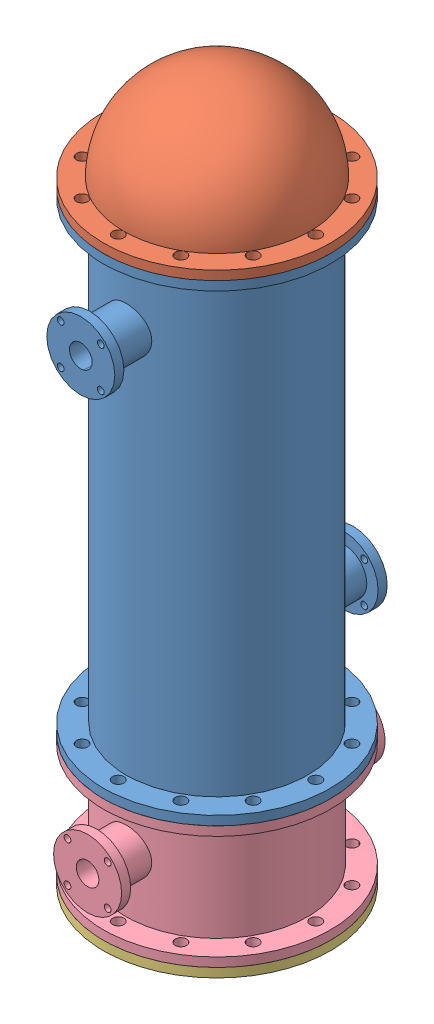
SolidWorks assembly Heat Exchangwr, configuration Default. Lengths in mm.
Overall size (500 1692.4 600).
12 component instances, 6 part files, 18 mates.
Components (placement in the parent):
- Tube Housing-1: Tube Housing [Default] at (499.3721 118.9236 1027.5542) size (500 1040 600)
- End Cap-1: End Cap [Default] at (499.3721 1158.9236 1027.5542) x (0 0 -1) z (1 0 0) size (500 225 500)
- Outside Flange-1: Outside Flange [Default] at (499.3721 -171.0764 1027.5542) size (500 20 500)
- Steam Channel-1: Steam Channel [Default] at (499.3721 -151.0764 1027.5542) size (500 540.34 580)
- Tubes and Holders-1: Tubes and Holders [Default] at (1394.8823 182.8892 1623.1997) x (0 1 0) z (-0.999974 0 -0.007153) size (1200 360 361.03)
  - Tubes-1: Tubes [Default] at (-63.9656 589.2251 899.7476) size (1200 360 360)
  - Semi flang-1: Semi flang [Default] at (96.0344 589.2251 910.6392) size (10 180 360)
  - Semi flang-2: Semi flang [Default] at (376.0344 589.2251 910.6392) size (10 180 360)
  - Semi flang-3: Semi flang [Default] at (806.0344 589.2251 910.6392) x (-1 0 0) z (0 0 1) size (10 180 360)
  - Semi flang-4: Semi flang [Default] at (656.0344 589.2251 910.6392) size (10 180 360)
  - Semi flang-5: Semi flang [Default] at (526.0344 589.2251 910.6392) x (-1 0 0) z (0 0 1) size (10 180 360)
  - Semi flang-6: Semi flang [Default] at (236.0344 589.2251 889.0756) x (1 0 0) z (0 0 -1) size (10 180 360)
Mates (geometry in assembly coordinates):
- Coincident1: coincident: plane of Tube Housing-1 through (499.3721 1158.9236 1027.5542) normal (0 1 0); plane of End Cap-1 through (499.3721 1158.9236 1027.5542) normal (0 -1 0)
- Distance1: distance = 0 mm: plane of End Cap-1 through (499.3721 1158.9236 1027.5542) normal (0 -1 0); plane of Tube Housing-1 through (499.3721 1158.9236 1027.5542) normal (0 1 0)
- Coincident3: coincident: circle of Tube Housing-1; cylinder of Tubes and Holders-1/Tubes-1 through (499.3721 138.9236 1027.5542) axis (0 -1 0) radius 180
- Coincident4: coincident: plane of Tube Housing-1 through (499.3721 118.9236 1027.5542) normal (0 -1 0); plane of Tubes and Holders-1/Tubes-1 through (499.3721 118.9236 1027.5542) normal (0 -1 0)
- Angle1: planar angle = 0 rad: cylinder of Tubes and Holders-1/Tubes-1 through (500.3352 118.9236 877.5573) axis (0 1 0) radius 7; cylinder of Tube Housing-1 through (499.3721 138.9236 1245.0542) axis (0 -1 0) radius 12.5
- Parallel5: parallel anti-aligned: plane of Tube Housing-1 through (499.3721 1158.9236 1027.5542) normal (0 1 0); plane of End Cap-1 through (499.3721 1158.9236 1027.5542) normal (0 -1 0)
- Distance3: distance = 20 mm: plane of Tube Housing-1 through (499.3721 1138.9236 1027.5542) normal (0 -1 0); plane of End Cap-1 through (499.3721 1158.9236 1027.5542) normal (0 -1 0)
- Coincident7: coincident anti-aligned: plane of Tube Housing-1 through (499.3721 118.9236 1027.5542) normal (0 -1 0); plane of Steam Channel-1 through (499.3721 118.9236 1027.5542) normal (0 1 0)
- Concentric3: concentric aligned: cylinder of Tube Housing-1 through (499.3721 1138.9236 1027.5542) axis (0 -1 0) radius 200; cylinder of Steam Channel-1 through (499.3721 98.9236 1027.5542) axis (0 -1 0) radius 200
- Concentric4: concentric: cylinder of Tube Housing-1 through (499.3721 1138.9236 1027.5542) axis (0 -1 0) radius 200; sphere of End Cap-1
- Parallel6: parallel aligned: plane of Tube Housing-1 through (499.3721 288.9236 727.5542) normal (0 0 -1); plane of Steam Channel-1 through (499.3721 -151.0764 732.5542) normal (0 0 -1)
- Parallel7: parallel: plane of Steam Channel-1 through (499.3721 -151.0764 1027.5542) normal (0 -1 0); plane of Tubes and Holders-1/Tubes-1 through (499.3721 118.9236 1027.5542) normal (0 -1 0)
- Parallel8: parallel: cylinder of Steam Channel-1 through (499.3721 -131.0764 810.0542) axis (0 -1 0) radius 12.5; cylinder of Tubes and Holders-1/Tubes-1 through (499.62 118.9236 977.5547) axis (0 1 0) radius 7
- Perpendicular1: perpendicular: plane of Steam Channel-1 through (319.3721 118.9236 1022.5542) normal (0 0 -1); plane of Tubes and Holders-1/Tubes-1 through (499.3721 118.9236 1027.5542) normal (0 -1 0)
- Concentric5: concentric aligned: cylinder of Tube Housing-1 through (608.1221 1158.9236 839.1937) axis (0 -1 0) radius 12.5; cylinder of End Cap-1 through (608.1221 1178.9236 839.1937) axis (0 -1 0) radius 12.5
- Lock1: lock: unknown of Steam Channel-1; unknown of Tubes and Holders-1/Tubes-1
- Coincident9: coincident anti-aligned: plane of Outside Flange-1 through (499.3721 -151.0764 1027.5542) normal (0 1 0); plane of Steam Channel-1 through (499.3721 -151.0764 1027.5542) normal (0 -1 0)
- Concentric9: concentric anti-aligned: cylinder of Outside Flange-1 through (499.3721 -171.0764 810.0542) axis (0 1 0) radius 12.5; cylinder of Steam Channel-1 through (499.3721 -131.0764 810.0542) axis (0 -1 0) radius 12.5
